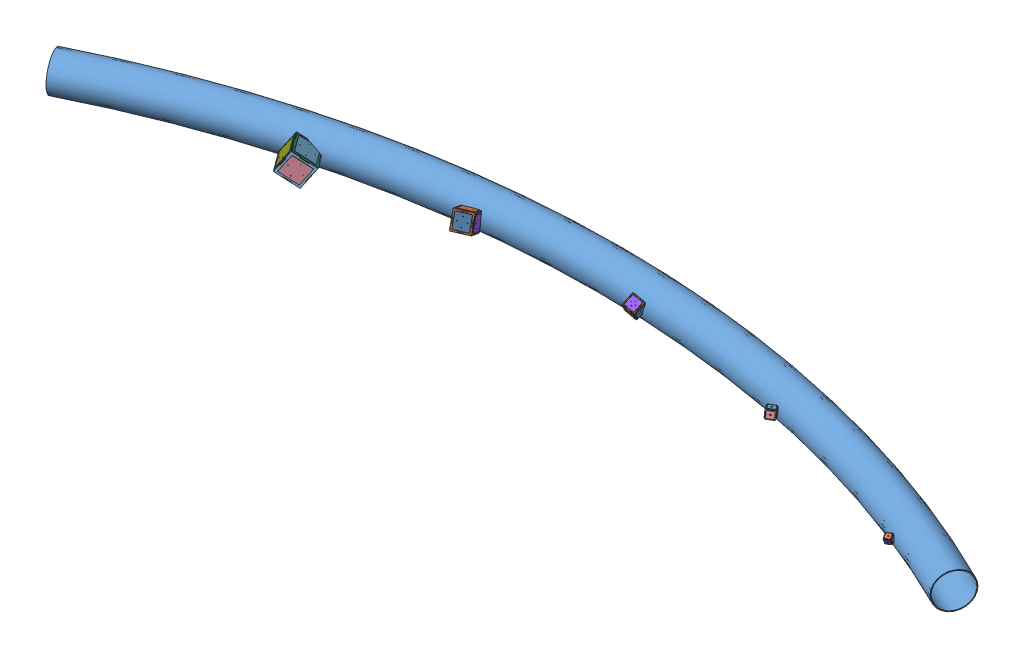
SolidWorks assembly tube2A, configuration Default. Lengths in mm.
Overall size (4303.96 169.52 662.44).
67 component instances, 62 part files, 18 mates.
Components (placement in the parent):
- cube_positions-1: cube_positions [Default] at (-3122.2059 -3460.4647 3595.7782) x (0.999848 0.008979 0.014977) z (-0.015946 0.119833 0.992666) size (10173.18 3894.08 5705.72) (hidden)
- tubes-1: tubes [tube2A] at origin size (4303.96 168.28 656.76)
- cube_15-1: cube_15 [cube15] at (1757.1943 7.1888 -324.7748) x (0.466813 -0.378836 0.799105) z (-0.87943 -0.103618 0.464614) size (31.46 31.46 31.46)
  - panel_R^cube_15-13: panel_R^cube_15 [cube01] x (-1 0 0) z (0 0 1) size (22.35 1.76 22.35) (virtual)
  - acrylic_R^cube_15-1: acrylic_R^cube_15 [A] at origin size (27.84 3.23 27.84) (virtual)
  - panel_O^cube_15-8: panel_O^cube_15 [cube01] x (0 -1 0) z (0 0 1) size (22.35 1.76 22.35) (virtual)
  - acrylic_O^cube_15-23: acrylic_O^cube_15 [A] x (0 1 0) z (0 0 1) size (27.84 3.23 27.84) (virtual)
  - panel_Y^cube_15-9: panel_Y^cube_15 [cube01] at origin size (22.35 1.76 22.35) (virtual)
  - acrylic_Y^cube_15-24: acrylic_Y^cube_15 [A] x (-1 0 0) z (0 0 1) size (27.84 3.23 27.84) (virtual)
  - panel_G^cube_15-10: panel_G^cube_15 [cube01] x (0 1 0) z (0 0 1) size (22.35 1.76 22.35) (virtual)
  - acrylic_G^cube_15-25: acrylic_G^cube_15 [A] x (0 -1 0) z (0 0 1) size (27.84 3.23 27.84) (virtual)
  - panel_C^cube_15-11: panel_C^cube_15 [cube01] x (-1 0 0) z (0 -1 0) size (22.35 1.76 22.35) (virtual)
  - acrylic_C^cube_15-26: acrylic_C^cube_15 [B] x (1 0 0) z (0 -1 0) size (27.84 3.23 27.84) (virtual)
  - panel_B^cube_15-13: panel_B^cube_15 [cube01] x (-1 0 0) z (0 1 0) size (22.35 1.76 22.35) (virtual)
  - acrylic_B^cube_15-27: acrylic_B^cube_15 [B] x (1 0 0) z (0 1 0) size (27.84 3.23 27.84) (virtual)
- cube_16-1: cube_16 [cube16] at (968.8015 9.4519 -559.7177) x (0.806784 -0.069825 -0.586706) z (0.590423 0.132849 0.796085) size (41.27 41.27 41.27)
  - panel_R^cube_16-13: panel_R^cube_16 [cube01] x (-1 0 0) z (0 0 1) size (30.48 1.59 30.48) (virtual)
  - acrylic_R^cube_16-1: acrylic_R^cube_16 [A] at origin size (38 3.23 38) (virtual)
  - panel_O^cube_16-8: panel_O^cube_16 [cube01] x (0 -1 0) z (0 0 1) size (30.48 1.59 30.48) (virtual)
  - acrylic_O^cube_16-23: acrylic_O^cube_16 [A] x (0 1 0) z (0 0 1) size (38 3.23 38) (virtual)
  - panel_Y^cube_16-9: panel_Y^cube_16 [cube01] at origin size (30.48 1.59 30.48) (virtual)
  - acrylic_Y^cube_16-24: acrylic_Y^cube_16 [A] x (-1 0 0) z (0 0 1) size (38 3.23 38) (virtual)
  - panel_G^cube_16-10: panel_G^cube_16 [cube01] x (0 1 0) z (0 0 1) size (30.48 1.59 30.48) (virtual)
  - acrylic_G^cube_16-25: acrylic_G^cube_16 [A] x (0 -1 0) z (0 0 1) size (38 3.23 38) (virtual)
  - panel_C^cube_16-11: panel_C^cube_16 [cube01] x (-1 0 0) z (0 -1 0) size (30.48 1.59 30.48) (virtual)
  - acrylic_C^cube_16-26: acrylic_C^cube_16 [B] x (1 0 0) z (0 -1 0) size (38 3.23 38) (virtual)
  - panel_B^cube_16-13: panel_B^cube_16 [cube01] x (-1 0 0) z (0 1 0) size (30.48 1.59 30.48) (virtual)
  - acrylic_B^cube_16-27: acrylic_B^cube_16 [B] x (1 0 0) z (0 1 0) size (38 3.23 38) (virtual)
- cube_17-1: cube_17 [cube17] at (219.4124 11.792 -668.2944) x (0.954748 -0.289413 -0.068523) z (-0.098768 -0.525851 0.844823) size (59.06 59.06 59.06)
  - panel_R^cube_17-13: panel_R^cube_17 [cube01] x (-1 0 0) z (0 0 1) size (44.7 1.59 44.7) (virtual)
  - acrylic_R^cube_17-1: acrylic_R^cube_17 [A] at origin size (55.78 3.23 55.78) (virtual)
  - panel_O^cube_17-8: panel_O^cube_17 [cube01] x (0 -1 0) z (0 0 1) size (44.7 1.59 44.7) (virtual)
  - acrylic_O^cube_17-23: acrylic_O^cube_17 [A] x (0 1 0) z (0 0 1) size (55.78 3.23 55.78) (virtual)
  - panel_Y^cube_17-9: panel_Y^cube_17 [cube01] at origin size (44.7 1.59 44.7) (virtual)
  - acrylic_Y^cube_17-24: acrylic_Y^cube_17 [A] x (-1 0 0) z (0 0 1) size (55.78 3.23 55.78) (virtual)
  - panel_G^cube_17-10: panel_G^cube_17 [cube01] x (0 1 0) z (0 0 1) size (44.7 1.59 44.7) (virtual)
  - acrylic_G^cube_17-25: acrylic_G^cube_17 [A] x (0 -1 0) z (0 0 1) size (55.78 3.23 55.78) (virtual)
  - panel_C^cube_17-11: panel_C^cube_17 [cube01] x (-1 0 0) z (0 -1 0) size (44.7 1.59 44.7) (virtual)
  - acrylic_C^cube_17-26: acrylic_C^cube_17 [B] x (1 0 0) z (0 -1 0) size (55.78 3.23 55.78) (virtual)
  - panel_B^cube_17-13: panel_B^cube_17 [cube01] x (-1 0 0) z (0 1 0) size (44.7 1.59 44.7) (virtual)
  - acrylic_B^cube_17-27: acrylic_B^cube_17 [B] x (1 0 0) z (0 1 0) size (55.78 3.23 55.78) (virtual)
- cube_18-1: cube_18 [cube18] at (-522.2233 15.3473 -617.0525) x (0.916882 -0.004667 -0.399132) z (0.359767 0.442803 0.821276) size (81.92 81.92 81.92)
  - panel_R^cube_18-13: panel_R^cube_18 [cube01] x (-1 0 0) z (0 0 1) size (62.99 1.59 62.99) (virtual)
  - acrylic_R^cube_18-1: acrylic_R^cube_18 [A] at origin size (78.64 3.23 78.64) (virtual)
  - panel_O^cube_18-8: panel_O^cube_18 [cube01] x (0 -1 0) z (0 0 1) size (62.99 1.59 62.99) (virtual)
  - acrylic_O^cube_18-23: acrylic_O^cube_18 [A] x (0 1 0) z (0 0 1) size (78.64 3.23 78.64) (virtual)
  - panel_Y^cube_18-9: panel_Y^cube_18 [cube01] at origin size (62.99 1.59 62.99) (virtual)
  - acrylic_Y^cube_18-24: acrylic_Y^cube_18 [A] x (-1 0 0) z (0 0 1) size (78.64 3.23 78.64) (virtual)
  - panel_G^cube_18-10: panel_G^cube_18 [cube01] x (0 1 0) z (0 0 1) size (62.99 1.59 62.99) (virtual)
  - acrylic_G^cube_18-25: acrylic_G^cube_18 [A] x (0 -1 0) z (0 0 1) size (78.64 3.23 78.64) (virtual)
  - panel_C^cube_18-11: panel_C^cube_18 [cube01] x (-1 0 0) z (0 -1 0) size (62.99 1.59 62.99) (virtual)
  - acrylic_C^cube_18-26: acrylic_C^cube_18 [B] x (1 0 0) z (0 -1 0) size (78.64 3.23 78.64) (virtual)
  - panel_B^cube_18-13: panel_B^cube_18 [cube01] x (-1 0 0) z (0 1 0) size (62.99 1.59 62.99) (virtual)
  - acrylic_B^cube_18-27: acrylic_B^cube_18 [B] x (1 0 0) z (0 1 0) size (78.64 3.23 78.64) (virtual)
- cube_19-1: cube_19 [cube19] at (-1183.1884 -5.1426 -489.4193) x (0.660298 -0.557655 -0.503018) z (0.583277 -0.041114 0.811232) size (112.39 112.39 112.39)
  - panel_R^cube_19-13: panel_R^cube_19 [cube01] x (-1 0 0) z (0 0 1) size (87.38 1.59 87.38) (virtual)
  - acrylic_R^cube_19-1: acrylic_R^cube_19 [A] at origin size (109.12 3.23 109.12) (virtual)
  - panel_O^cube_19-8: panel_O^cube_19 [cube01] x (0 -1 0) z (0 0 1) size (87.38 1.59 87.38) (virtual)
  - acrylic_O^cube_19-23: acrylic_O^cube_19 [A] x (0 1 0) z (0 0 1) size (109.12 3.23 109.12) (virtual)
  - panel_Y^cube_19-9: panel_Y^cube_19 [cube01] at origin size (87.38 1.59 87.38) (virtual)
  - acrylic_Y^cube_19-24: acrylic_Y^cube_19 [A] x (-1 0 0) z (0 0 1) size (109.12 3.23 109.12) (virtual)
  - panel_G^cube_19-10: panel_G^cube_19 [cube01] x (0 1 0) z (0 0 1) size (87.38 1.59 87.38) (virtual)
  - acrylic_G^cube_19-25: acrylic_G^cube_19 [A] x (0 -1 0) z (0 0 1) size (109.12 3.23 109.12) (virtual)
  - panel_C^cube_19-11: panel_C^cube_19 [cube01] x (-1 0 0) z (0 -1 0) size (87.38 1.59 87.38) (virtual)
  - acrylic_C^cube_19-26: acrylic_C^cube_19 [B] x (1 0 0) z (0 -1 0) size (109.12 3.23 109.12) (virtual)
  - panel_B^cube_19-13: panel_B^cube_19 [cube01] x (-1 0 0) z (0 1 0) size (87.38 1.59 87.38) (virtual)
  - acrylic_B^cube_19-27: acrylic_B^cube_19 [B] x (1 0 0) z (0 1 0) size (109.12 3.23 109.12) (virtual)
Mates (geometry in assembly coordinates):
- Coincident1: coincident aligned: plane of cube_positions-1 through (-1103.7628 -71.395 -556.5979) normal (0.473069 0.829054 -0.29812); plane of cube_19-1/panel_R^cube_19-13 through (-1165.7598 -64.1331 -634.7822) normal (0.473069 0.829054 -0.29812)
- Coincident2: coincident aligned: plane of cube_positions-1 through (-1173.453 -12.538 -503.5077) normal (0.583277 -0.041114 0.811232); plane of cube_19-1/panel_C^cube_19-11 through (-1113.4167 -78.6108 -550.0225) normal (0.583277 -0.041114 0.811232)
- Coincident3: coincident aligned: plane of cube_positions-1 through (-1173.453 -12.538 -503.5077) normal (-0.660298 0.557655 0.503018); plane of cube_19-1/panel_O^cube_19-8 through (-1237.6318 -18.8024 -580.8086) normal (-0.660298 0.557655 0.503018)
- Coincident4: coincident aligned: plane of cube_positions-1 through (-557.1841 37.9489 -619.0784) normal (-0.172904 0.896607 -0.407677); plane of cube_18-1/panel_R^cube_18-13 through (-516.8192 5.5282 -707.5012) normal (-0.172904 0.896607 -0.407677)
- Coincident5: coincident aligned: plane of cube_positions-1 through (-474.4505 -30.4734 -618.4297) normal (0.359767 0.442803 0.821276); plane of cube_18-1/panel_C^cube_18-11 through (-489.1169 29.1275 -644.1397) normal (0.359767 0.442803 0.821276)
- Coincident6: coincident aligned: plane of cube_positions-1 through (-544.0577 -30.1191 -588.1287) normal (-0.916882 0.004667 0.399132); plane of cube_18-1/panel_O^cube_18-8 through (-581.6145 -2.6169 -674.7255) normal (-0.916882 0.004667 0.399132)
- Coincident7: coincident aligned: plane of cube_positions-1 through (254.04 -31.0668 -675.8304) normal (-0.098768 -0.525851 0.844823); plane of cube_17-1/panel_C^cube_17-11 through (250.2912 -36.2798 -679.5134) normal (-0.098768 -0.525851 0.844823)
- Coincident8: coincident aligned: plane of cube_positions-1 through (259.3436 -2.8299 -721.1953) normal (0.280536 0.799826 0.53064); plane of cube_17-1/panel_R^cube_17-13 through (257.4282 -3.2597 -719.5348) normal (0.280536 0.799826 0.53064)
- Coincident9: coincident aligned: plane of cube_positions-1 through (208.0759 12.7109 -717.5158) normal (-0.954748 0.289413 0.068523); plane of cube_17-1/panel_O^cube_17-8 through (205.8834 6.0157 -719.7874) normal (-0.954748 0.289413 0.068523)
- Coincident10: coincident: plane of cube_positions-1 through (994.1488 23.1535 -570.1938) normal (0.590423 0.132849 0.796085); point of cube_16-1/panel_C^cube_16-11
- Coincident14: coincident: plane of cube_positions-1 through (942.4063 20.8195 -577.9477) normal (-0.806784 0.069825 0.586706); plane of cube_16-1/panel_O^cube_16-8 through (943.2091 15.6366 -576.2269) normal (-0.806784 0.069825 0.586706)
- Coincident15: coincident aligned: plane of cube_positions-1 through (972.2837 18.2337 -599.6751) normal (-0.022357 0.988674 -0.148407); plane of cube_16-1/panel_R^cube_16-13 through (972.0338 18.4679 -598.0775) normal (-0.022357 0.988674 -0.148407)
- Coincident16: coincident: plane of cube_positions-1 through (1765.0351 20.3249 -347.2955) normal (0.093211 0.919645 0.381531); plane of cube_15-1/panel_R^cube_15-13 through (1776.5677 13.1415 -332.7982) normal (0.093211 0.919645 0.381531)
- Coincident17: coincident: plane of cube_positions-1 through (1765.0351 20.3249 -347.2955) normal (0.093211 0.919645 0.381531); plane of cube_15-1/panel_R^cube_15-13 through (1776.5677 13.1415 -332.7982) normal (0.093211 0.919645 0.381531)
- Coincident18: coincident: plane of cube_positions-1 through (1743.866 17.8307 -336.1117) normal (-0.87943 -0.103618 0.464614); plane of cube_15-1/panel_C^cube_15-11 through (1752.6491 6.342 -322.0491) normal (-0.87943 -0.103618 0.464614)
- Coincident19: coincident aligned: plane of cube_positions-1 through (1776.2719 11.2058 -328.06) normal (0.466813 -0.378836 0.799105); plane of ? through (1776.1212 -13.1037 -339.4965) normal (0.466813 -0.378836 0.799105)
- PLANE1: unknown = 168.275 mm: plane of tubes-1 through (0 -84.1375 0) normal (0 1 0)
- placement info: unknown = 79.6653 mm: unknown of ?; unknown of ?; unknown of ?; unknown of cube_18-1/acrylic_B^cube_18-27; unknown of ?; unknown of tubes-1
